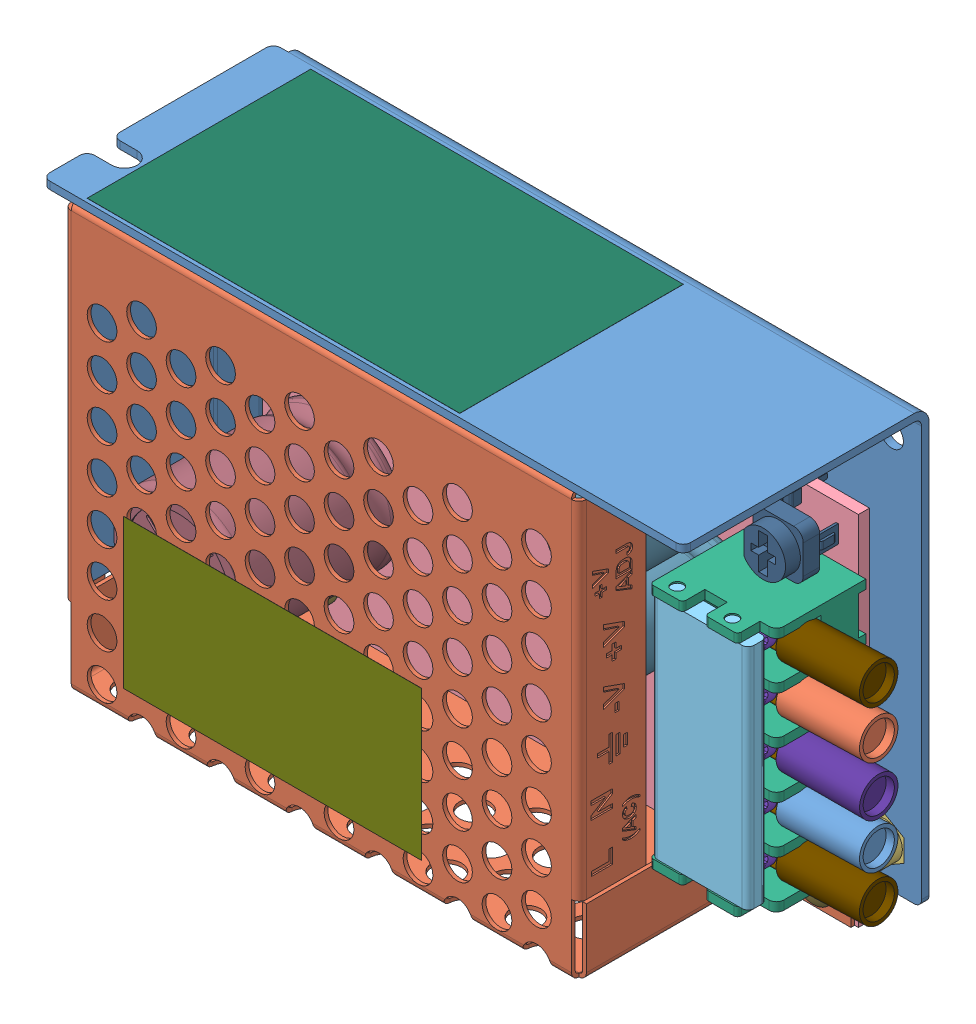
SolidWorks assembly Power Supply S-60-12, configuration Default. Lengths in mm.
Overall size (95.75 58.03 33.03).
43 component instances, 20 part files, 14 mates.
Components (placement in the parent):
- BaseS-60-12^Power Supply S-60-12-1: BaseS-60-12^Power Supply S-60-12 [Default] at origin size (86.01 58.01 33.01) (virtual)
- CoverS-60-12^Power Supply S-60-12-1: CoverS-60-12^Power Supply S-60-12 [Default] at (-0.0001 0 0) size (81.64 57 32) (virtual)
- TorrettaS-60-12^Power Supply S-60-12-1: TorrettaS-60-12^Power Supply S-60-12 [Default] at origin size (5.2 6 7) (virtual)
- Basetta^Power Supply S-60-12-1: Basetta^Power Supply S-60-12 [Default] at (0 0 7) size (80 54 1.5) (virtual)
- Screw TerminalS-60-12-1: Screw TerminalS-60-12 [Default] at origin size (14 33 18)
  - Cover_0^Screw TerminalS-60-12-1: Cover_0^Screw TerminalS-60-12 [Default] at (60.5 25.5 20.7) x (0 1 0) z (0 0 1) size (32.6 13 2.6) (virtual)
  - Corpo^Screw TerminalS-60-12-1: Corpo^Screw TerminalS-60-12 [Default] at (79 25.5 8.5) x (0 1 0) z (0 0 1) size (33 14 15) (virtual)
  - GruppoVite^Screw TerminalS-60-12-1: GruppoVite^Screw TerminalS-60-12 [Default] at origin size (7.91 5.27 13.79) (virtual)
    - DadoBasso^GruppoVite_Screw TerminalS-60-12-1: DadoBasso^GruppoVite_Screw TerminalS-60-12 [Default] at (79.8845 28.4079 8.4556) x (0 1 0) z (0 0 1) size (5.27 7.91 9.5) (virtual)
    - M3x06_MOD v4^GruppoVite_Screw TerminalS-60-12-1: M3x06_MOD v4^GruppoVite_Screw TerminalS-60-12 [Default] at (80.5 12.78 16.9) x (0 1 0) z (0 0 1) size (4.5 4.5 8.39) (virtual)
    - DadoAlto^GruppoVite_Screw TerminalS-60-12-1: DadoAlto^GruppoVite_Screw TerminalS-60-12 [Default] at (80.45 -12.22 15.7) x (0 1 0) z (0 0 1) size (4.8 6.11 1.26) (virtual)
  - GruppoVite^Screw TerminalS-60-12-2: GruppoVite^Screw TerminalS-60-12 [Default] at (0 6.3694 0) size (7.91 5.27 13.79) (virtual)
    - DadoBasso^GruppoVite_Screw TerminalS-60-12-1: DadoBasso^GruppoVite_Screw TerminalS-60-12 [Default] at (79.8845 28.4079 8.4556) x (0 1 0) z (0 0 1) size (5.27 7.91 9.5) (virtual)
    - M3x06_MOD v4^GruppoVite_Screw TerminalS-60-12-1: M3x06_MOD v4^GruppoVite_Screw TerminalS-60-12 [Default] at (80.5 12.78 16.9) x (0 1 0) z (0 0 1) size (4.5 4.5 8.39) (virtual)
    - DadoAlto^GruppoVite_Screw TerminalS-60-12-1: DadoAlto^GruppoVite_Screw TerminalS-60-12 [Default] at (80.45 -12.22 15.7) x (0 1 0) z (0 0 1) size (4.8 6.11 1.26) (virtual)
  - GruppoVite^Screw TerminalS-60-12-3: GruppoVite^Screw TerminalS-60-12 [Default] at (0 12.7319 0) size (7.91 5.27 13.79) (virtual)
    - DadoBasso^GruppoVite_Screw TerminalS-60-12-1: DadoBasso^GruppoVite_Screw TerminalS-60-12 [Default] at (79.8845 28.4079 8.4556) x (0 1 0) z (0 0 1) size (5.27 7.91 9.5) (virtual)
    - M3x06_MOD v4^GruppoVite_Screw TerminalS-60-12-1: M3x06_MOD v4^GruppoVite_Screw TerminalS-60-12 [Default] at (80.5 12.78 16.9) x (0 1 0) z (0 0 1) size (4.5 4.5 8.39) (virtual)
    - DadoAlto^GruppoVite_Screw TerminalS-60-12-1: DadoAlto^GruppoVite_Screw TerminalS-60-12 [Default] at (80.45 -12.22 15.7) x (0 1 0) z (0 0 1) size (4.8 6.11 1.26) (virtual)
  - GruppoVite^Screw TerminalS-60-12-4: GruppoVite^Screw TerminalS-60-12 [Default] at (0 19.0736 0) size (7.91 5.27 13.79) (virtual)
    - DadoBasso^GruppoVite_Screw TerminalS-60-12-1: DadoBasso^GruppoVite_Screw TerminalS-60-12 [Default] at (79.8845 28.4079 8.4556) x (0 1 0) z (0 0 1) size (5.27 7.91 9.5) (virtual)
    - M3x06_MOD v4^GruppoVite_Screw TerminalS-60-12-1: M3x06_MOD v4^GruppoVite_Screw TerminalS-60-12 [Default] at (80.5 12.78 16.9) x (0 1 0) z (0 0 1) size (4.5 4.5 8.39) (virtual)
    - DadoAlto^GruppoVite_Screw TerminalS-60-12-1: DadoAlto^GruppoVite_Screw TerminalS-60-12 [Default] at (80.45 -12.22 15.7) x (0 1 0) z (0 0 1) size (4.8 6.11 1.26) (virtual)
  - GruppoVite^Screw TerminalS-60-12-5: GruppoVite^Screw TerminalS-60-12 [Default] at (0 25.4377 0) size (7.91 5.27 13.79) (virtual)
    - DadoBasso^GruppoVite_Screw TerminalS-60-12-1: DadoBasso^GruppoVite_Screw TerminalS-60-12 [Default] at (79.8845 28.4079 8.4556) x (0 1 0) z (0 0 1) size (5.27 7.91 9.5) (virtual)
    - M3x06_MOD v4^GruppoVite_Screw TerminalS-60-12-1: M3x06_MOD v4^GruppoVite_Screw TerminalS-60-12 [Default] at (80.5 12.78 16.9) x (0 1 0) z (0 0 1) size (4.5 4.5 8.39) (virtual)
    - DadoAlto^GruppoVite_Screw TerminalS-60-12-1: DadoAlto^GruppoVite_Screw TerminalS-60-12 [Default] at (80.45 -12.22 15.7) x (0 1 0) z (0 0 1) size (4.8 6.11 1.26) (virtual)
- Pot - RES_VAR1 v1^Power Supply S-60-12-1: Pot - RES_VAR1 v1^Power Supply S-60-12 [Default] at (79.625 45.45 13.9) x (0 1 0) z (1 0 0) size (6.5 10.9 7.05) (virtual)
- LED 3mm Green v1^Power Supply S-60-12-1: LED 3mm Green v1^Power Supply S-60-12 [Default] at (74.75 51.48 4.7) x (0 1 0) z (1 0 0) size (3.58 10.11 3.85) (virtual)
- M3x06_ISO7045 v1^Power Supply S-60-12-1: M3x06_ISO7045 v1^Power Supply S-60-12 [Default] at (81 5.5 9) size (5.65 6.29 8.72) (virtual)
- M3x06_ISO7045 v1^Power Supply S-60-12-3: M3x06_ISO7045 v1^Power Supply S-60-12 [Default] at (12.5 5.5 8.5) size (5.65 6.29 8.72) (virtual)
- CAP_RAD_D18x20_POL_BK v1^Power Supply S-60-12-1: CAP_RAD_D18x20_POL_BK v1^Power Supply S-60-12 [Default] at (15.7292 18.5329 8.5) size (18.5 18.5 24.51) (virtual)
- CAP_RAD_D10x16_POL_BK v1^Power Supply S-60-12-1: CAP_RAD_D10x16_POL_BK v1^Power Supply S-60-12 [Default] at (65 44.0389 8.5) size (10.5 10.5 20.01) (virtual)
- M3x06_ISO7045 v1^Power Supply S-60-12-4: M3x06_ISO7045 v1^Power Supply S-60-12 [Default] at (2.8599 5 20.5) x (0 0 1) z (-1 0 0) size (5.65 6.29 8.72) (virtual)
- CAP_RAD_D10x16_POL_BK v1^Power Supply S-60-12-2: CAP_RAD_D10x16_POL_BK v1^Power Supply S-60-12 [Default] at (66 32.9611 8.5) size (10.5 10.5 20.01) (virtual)
- Img02^Power Supply S-60-12-1: Img02^Power Supply S-60-12 [Default] at (5.5 58 102.5) x (1 0 0) z (0 1 0) size (50 30 0.02) (virtual)
- Img01^Power Supply S-60-12-1: Img01^Power Supply S-60-12 [Default] at (50.8999 -26 33) x (-1 0 0) z (0 0 1) size (40 20 0.02) (virtual)
- TorrettaS-60-12^Power Supply S-60-12-2: TorrettaS-60-12^Power Supply S-60-12 [Default] at (-68.5 0 0) size (5.2 6 7) (virtual)
- Insulated Ring Terminal ID 3mm-Green-1: Insulated Ring Terminal ID 3mm-Green [Default] at (80.5 25.5119 14.7) x (0.002516 -0.999997 0) z (-0.999997 -0.002516 0) size (5.54 5.16 31.83)
- Insulated Ring Terminal ID 3mm-Red-1: Insulated Ring Terminal ID 3mm-Red [Black] at (80.5 38.2177 14.7) x (0.033819 -0.999428 0) z (-0.999428 -0.033819 0) size (5.54 5.16 17.93)
- Insulated Ring Terminal ID 3mm-Red-2: Insulated Ring Terminal ID 3mm-Red [Black] at (80.5 12.78 14.7) x (0.033819 -0.999428 0) z (-0.999428 -0.033819 0) size (5.54 5.16 17.93)
- Insulated Ring Terminal ID 3mm-White-1: Insulated Ring Terminal ID 3mm-White [Default] at (80.5 19.1494 14.7) x (0.023217 -0.99973 0) z (-0.99973 -0.023217 0) size (5.54 5.16 17.93)
- Insulated Ring Terminal ID 3mm-1: Insulated Ring Terminal ID 3mm [Default] at (80.5 31.8536 14.7) x (0.029288 -0.999571 0) z (-0.999571 -0.029288 0) size (5.54 5.16 17.93)
Mates (geometry in assembly coordinates):
- Coincident1: coincident anti-aligned: plane of BaseS-60-12^Power Supply S-60-12-1 through (9.9019 4 0) normal (0.5 0.866025 0); plane of TorrettaS-60-12-2 through (9.9019 4 0) normal (-0.5 -0.866025 0)
- Coincident2: coincident aligned: plane of BaseS-60-12^Power Supply S-60-12-1 through (0 0 0) normal (0 0 -1); plane of TorrettaS-60-12-2 through (9.9019 2.5 0) normal (0 0 -1)
- Coincident3: coincident anti-aligned: plane of BaseS-60-12^Power Supply S-60-12-1 through (12.5 8.5 0) normal (0.5 -0.866025 0); plane of TorrettaS-60-12-2 through (12.5 8.5 0) normal (-0.5 0.866025 0)
- Coincident4: coincident anti-aligned: plane of Screw TerminalS-60-12-1/GruppoVite^Screw TerminalS-60-12-1/DadoAlto^GruppoVite_Screw TerminalS-60-12-1 through (83.2 10.73 16.9) normal (0 0 1); plane of ? through (81.0304 12.63 16.9) normal (0 0 -1)
- Coincident5: coincident anti-aligned: plane of Screw TerminalS-60-12-1/Copy of GruppoVite^Screw TerminalS-60-12-3/DadoBasso-1 through (76.9 27.7919 14.7) normal (0 0 1); plane of Insulated Ring Terminal ID 3mm-Green-1 through (77.6053 28.3858 14.7) normal (0 0 -1)
- Concentric1: concentric anti-aligned: cylinder of Screw TerminalS-60-12-1/Copy of GruppoVite^Screw TerminalS-60-12-3/M3x06_MOD v4-1 through (80.5 25.5119 15.6659) axis (0 0 -1) radius 1.4635; cylinder of Insulated Ring Terminal ID 3mm-Green-1 through (80.5 25.5119 14.7) axis (0 0 1) radius 1.8415
- Coincident6: coincident anti-aligned: plane of Screw TerminalS-60-12-1/Copy of GruppoVite^Screw TerminalS-60-12-5/DadoBasso-1 through (76.9 40.4977 14.7) normal (0 0 1); plane of Insulated Ring Terminal ID 3mm-Red-1 through (77.5167 40.9995 14.7) normal (0 0 -1)
- Concentric2: concentric anti-aligned: cylinder of Screw TerminalS-60-12-1/Copy of GruppoVite^Screw TerminalS-60-12-5/M3x06_MOD v4-1 through (80.5 38.2177 15.6659) axis (0 0 -1) radius 1.4635; cylinder of Insulated Ring Terminal ID 3mm-Red-1 through (80.5 38.2177 14.7) axis (0 0 1) radius 1.8415
- Coincident7: coincident anti-aligned: plane of Screw TerminalS-60-12-1/Copy of GruppoVite^Screw TerminalS-60-12-1/DadoBasso-1 through (76.9 15.06 14.7) normal (0 0 1); plane of Insulated Ring Terminal ID 3mm-Red-2 through (77.5167 15.5618 14.7) normal (0 0 -1)
- Concentric3: concentric anti-aligned: cylinder of Screw TerminalS-60-12-1/Copy of GruppoVite^Screw TerminalS-60-12-1/M3x06_MOD v4-1 through (80.5 12.78 15.6659) axis (0 0 -1) radius 1.4635; cylinder of Insulated Ring Terminal ID 3mm-Red-2 through (80.5 12.78 14.7) axis (0 0 1) radius 1.8415
- Coincident8: coincident anti-aligned: plane of Screw TerminalS-60-12-1/Copy of GruppoVite^Screw TerminalS-60-12-2/DadoBasso-1 through (76.9 21.4294 14.7) normal (0 0 1); plane of Insulated Ring Terminal ID 3mm-White-1 through (77.5464 21.9627 14.7) normal (0 0 -1)
- Concentric4: concentric anti-aligned: cylinder of Screw TerminalS-60-12-1/Copy of GruppoVite^Screw TerminalS-60-12-2/M3x06_MOD v4-1 through (80.5 19.1494 15.6659) axis (0 0 -1) radius 1.4635; cylinder of Insulated Ring Terminal ID 3mm-White-1 through (80.5 19.1494 14.7) axis (0 0 1) radius 1.8415
- Coincident9: coincident anti-aligned: plane of Screw TerminalS-60-12-1/Copy of GruppoVite^Screw TerminalS-60-12-4/DadoBasso-1 through (76.9 34.1336 14.7) normal (0 0 1); plane of Insulated Ring Terminal ID 3mm-1 through (77.5294 34.6489 14.7) normal (0 0 -1)
- Concentric5: concentric anti-aligned: cylinder of Screw TerminalS-60-12-1/Copy of GruppoVite^Screw TerminalS-60-12-4/M3x06_MOD v4-1 through (80.5 31.8536 15.6659) axis (0 0 -1) radius 1.4635; cylinder of Insulated Ring Terminal ID 3mm-1 through (80.5 31.8536 14.7) axis (0 0 1) radius 1.8415
